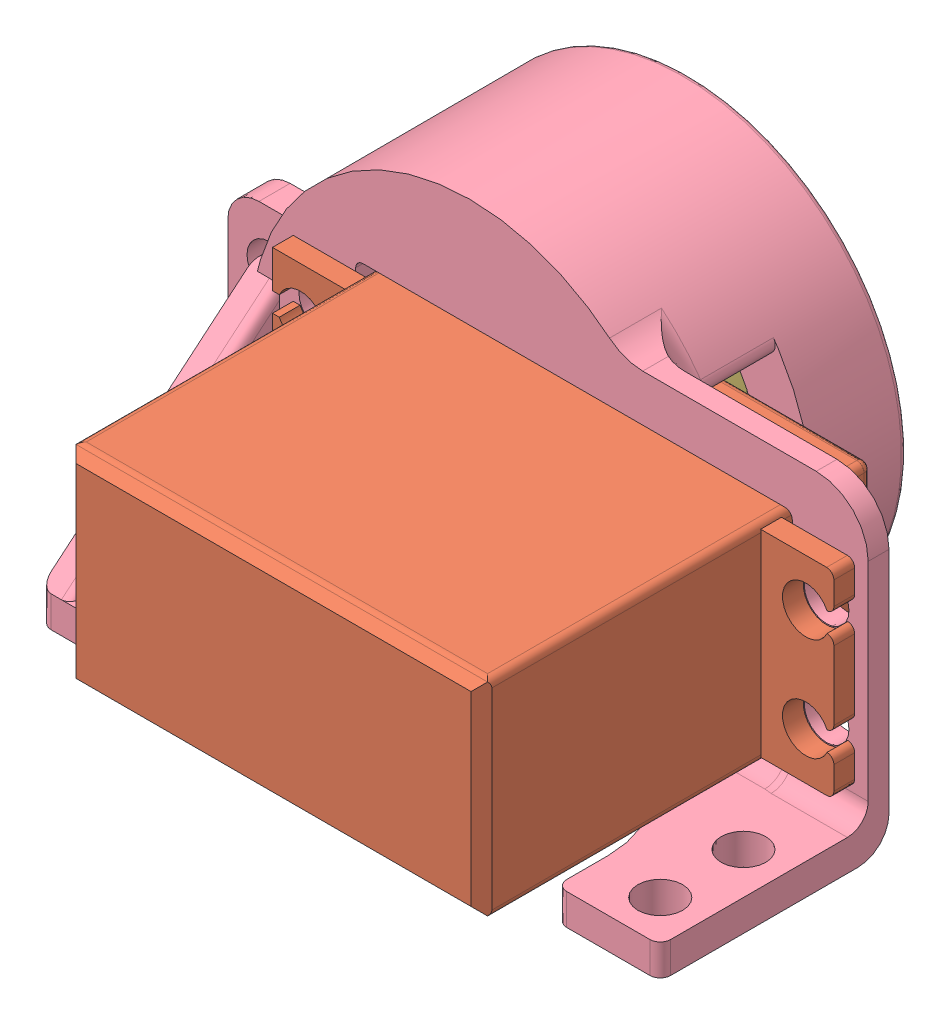
SolidWorks assembly 腿部固定总成_对称, configuration 默认. Lengths in mm.
Overall size (67.6 48.35 50.13).
4 component instances, 4 part files, 7 mates.
Components (placement in the parent):
- 6706一30x37x4轴承-1: 6706一30x37x4轴承 [默认] at (4.3976 -20.383 61.6212) x (-0.923728 -0.383049 0) z (0 0 -1) size (37 37 4)
- MG996R-1: MG996R [默认] at (34.3976 -30.333 107.5212) x (-1 0 0) z (0 -1 0) size (54 43.2 19.9)
- 舵盘-1: 舵盘 [默认] at (4.3976 -20.4396 64.3212) size (20 20 4.5)
- 舵机固定件_轴承_机体部分_对称-1: 舵机固定件_轴承_机体部分_对称 [默认] at (-6.6024 -9.883 120.6212) x (1 0 0) z (0 0 -1) size (67.6 42 41.23)
Mates (geometry in assembly coordinates):
- 重合3: coincident anti-aligned: plane of MG996R-1 through (4.3976 -20.4396 64.3212) normal (0 0 -1); plane of 舵盘-1 through (4.3976 -20.4396 64.3212) normal (0 0 1)
- 同心9: concentric aligned: circle of MG996R-1; circle of 舵盘-1
- 重合4: coincident anti-aligned: plane of MG996R-1 through (34.3976 -30.333 78.6212) normal (0 0 -1); plane of 舵机固定件_轴承_机体部分_对称-1 through (-6.6024 -9.883 78.6212) normal (0 0 1)
- 同心10: concentric aligned: circle of MG996R-1; circle of 舵机固定件_轴承_机体部分_对称-1
- 同心11: concentric aligned: circle of MG996R-1; circle of 舵机固定件_轴承_机体部分_对称-1
- 同心12: concentric aligned: circle of 6706一30x37x4轴承-1; circle of 舵机固定件_轴承_机体部分_对称-1
- 重合5: coincident anti-aligned: plane of 6706一30x37x4轴承-1 through (4.3976 -20.383 61.6212) normal (0 0 1); plane of 舵机固定件_轴承_机体部分_对称-1 through (-6.6024 -9.883 61.6212) normal (0 0 -1)
